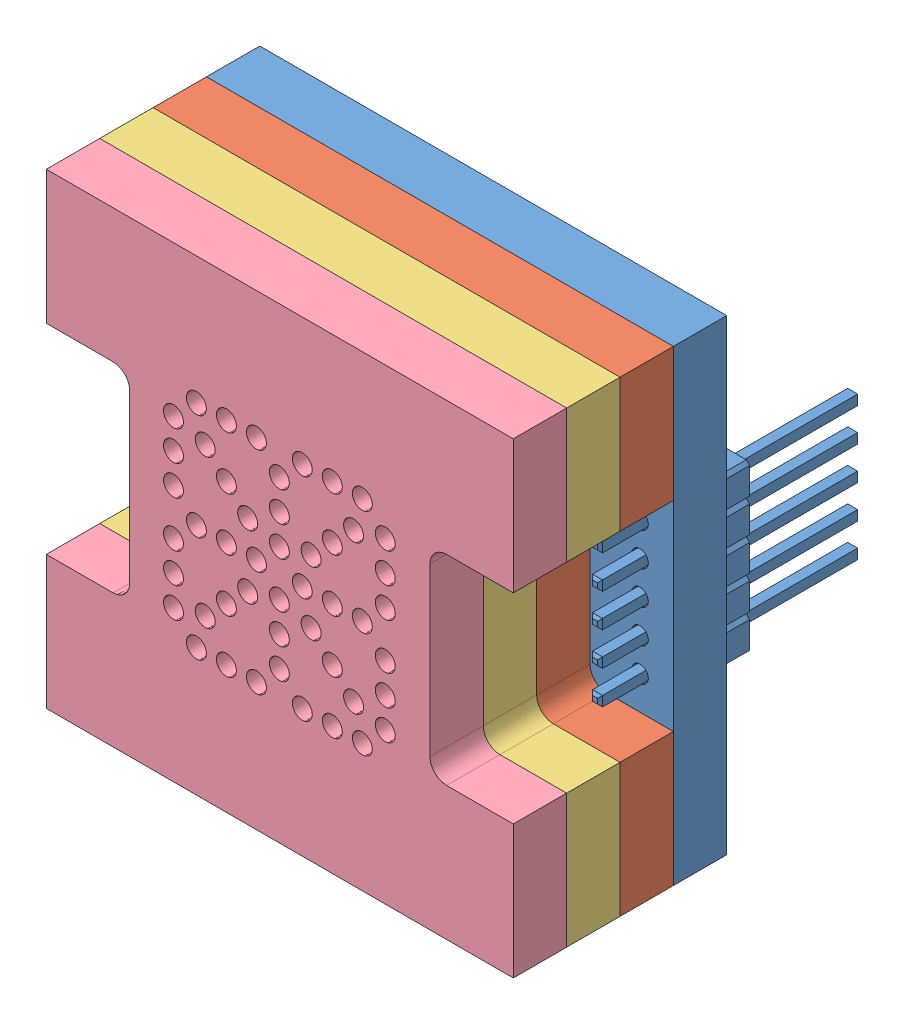
SolidWorks assembly ufc_v4_comm_disp, configuration Default. Lengths in mm.
Overall size (14 14 11.25).
4 component instances, 4 part files, 10 mates.
Components (placement in the parent):
- ufc_v4_comm-1: ufc_v4_comm [Default] at origin size (14 14 7.8)
- ufc_v4_comm_layer2-1: ufc_v4_comm_layer2 [Default] at (0 0 1.6) size (14 14 1.6)
- ufc_v4_comm_layer3-1: ufc_v4_comm_layer3 [Default] at (0 0 3.2) size (14 14 1.6)
- ufc_v4_comm_layer4-1: ufc_v4_comm_layer4 [Default] at (0 0 4.8) size (14 14 1.6)
Mates (geometry in assembly coordinates):
- Coincident1: coordinate: point of ufc_v4_comm-1
- Coincident2: coincident anti-aligned: plane of ufc_v4_comm-1 through (0 0 1.6) normal (0 0 1); plane of ufc_v4_comm_layer2-1 through (0 0 1.6) normal (0 0 -1)
- Coincident3: coincident anti-aligned: plane of ufc_v4_comm_layer2-1 through (0 0 3.2) normal (0 0 1); plane of ufc_v4_comm_layer3-1 through (0 0 3.2) normal (0 0 -1)
- Coincident4: coincident anti-aligned: plane of ufc_v4_comm_layer3-1 through (0 0 4.8) normal (0 0 1); plane of ufc_v4_comm_layer4-1 through (0 0 4.8) normal (0 0 -1)
- Coincident5: coincident aligned: plane of ufc_v4_comm-1 through (7 7 0) normal (1 0 0); plane of ufc_v4_comm_layer2-1 through (7 7 1.6) normal (1 0 0)
- Coincident6: coincident aligned: plane of ufc_v4_comm-1 through (7 7 0) normal (1 0 0); plane of ufc_v4_comm_layer3-1 through (7 7 3.2) normal (1 0 0)
- Coincident7: coincident aligned: plane of ufc_v4_comm-1 through (7 7 0) normal (1 0 0); plane of ufc_v4_comm_layer4-1 through (7 3 4.8) normal (1 0 0)
- Coincident8: coincident aligned: plane of ufc_v4_comm-1 through (-7 7 0) normal (0 1 0); plane of ufc_v4_comm_layer2-1 through (-7 7 1.6) normal (0 1 0)
- Coincident9: coincident aligned: plane of ufc_v4_comm-1 through (-7 7 0) normal (0 1 0); plane of ufc_v4_comm_layer3-1 through (-7 7 3.2) normal (0 1 0)
- Coincident10: coincident aligned: plane of ufc_v4_comm-1 through (-7 7 0) normal (0 1 0); plane of ufc_v4_comm_layer4-1 through (7 7 4.8) normal (0 1 0)
